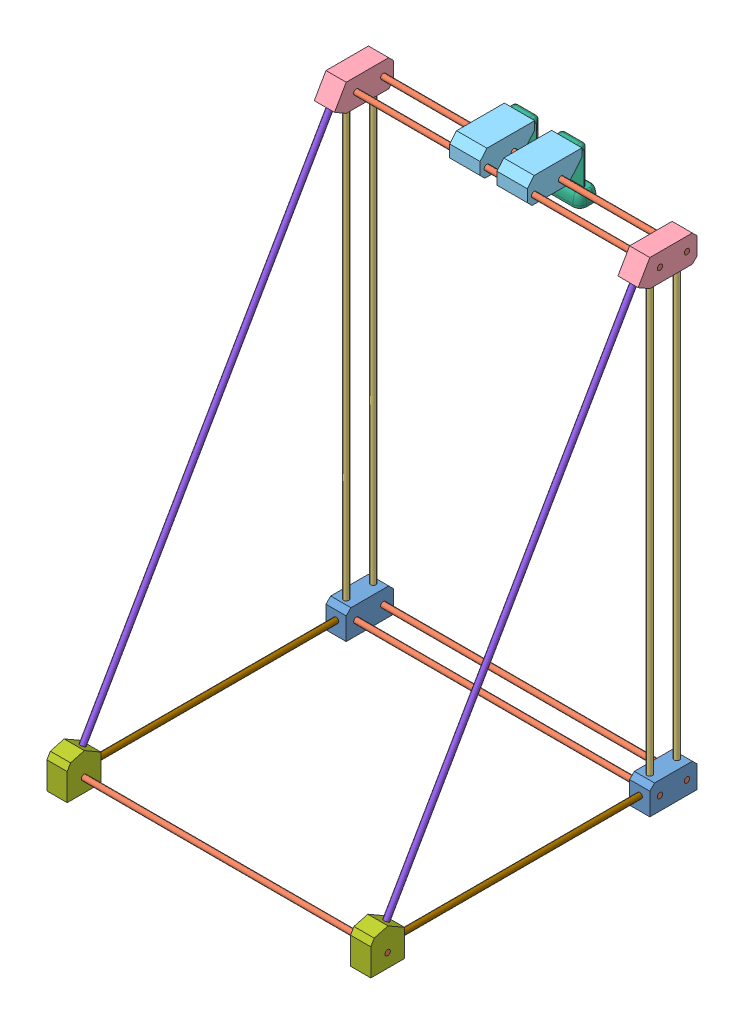
SolidWorks assembly M05, configuration Valor predeterminado. Lengths in mm.
Overall size (480 722.44 521.52).
27 component instances, 9 part files, 0 mates.
Components (placement in the parent):
- M04-1: M04 [Valor predeterminado] at (667.0132 -86.308 -633.8307) size (480 722.44 521.52)
  - M01-1: M01 [Valor predeterminado] at (-363.1678 -147.1166 448.121) size (480 40 70)
    - S02-1: S02 [Valor predeterminado] at (67.124 0.9923 31.879) size (30 40 70)
    - S02-2: S02 [Valor predeterminado] at (517.124 0.9923 31.879) size (30 40 70)
    - B01-1: B01 [Valor predeterminado] at (292.124 0.9923 51.879) x (0 -0.668888 0.743363) z (-1 0 0) size (7.94 7.94 480)
    - B01-2: B01 [Valor predeterminado] at (292.124 0.9923 11.879) x (0 0 1) z (-1 0 0) size (7.94 7.94 480)
  - B02-1: B02 [Valor predeterminado] at (153.9562 192.8457 460) x (0.715397 0 0.698718) z (-0.698718 0 0.715397) size (7.94 670 7.94)
  - B02-2: B02 [Valor predeterminado] at (153.9562 192.8457 500) x (0.738581 0 0.674164) z (-0.674164 0 0.738581) size (7.94 670 7.94)
  - B02-3: B02 [Valor predeterminado] at (-296.0438 192.8457 460) x (-0.715397 0 0.698718) z (-0.698718 0 -0.715397) size (7.94 670 7.94)
  - B02-4: B02 [Valor predeterminado] at (-296.0438 192.8457 500) x (-0.738581 0 0.674164) z (-0.674164 0 -0.738581) size (7.94 670 7.94)
  - M03-1: M03 [Valor predeterminado] at (140.416 512.3832 399.7341) size (480 74.25 125.32)
    - S03-1: S03 [Valor predeterminado] at (13.5401 19.4326 80.2659) size (30 40 87.32)
    - B01-1: B01 [Valor predeterminado] at (-211.4599 19.4326 60.2659) x (0 -0.924225 -0.381849) z (1 0 0) size (7.94 7.94 480)
    - B01-2: B01 [Valor predeterminado] at (-211.4599 19.4326 100.2659) x (0 -0.924225 -0.381849) z (1 0 0) size (7.94 7.94 480)
    - S03-2: S03 [Valor predeterminado] at (-436.4599 19.4326 80.2659) size (30 40 87.32)
    - S05-1: S05 [Valor predeterminado] at (-250.5177 19.4326 80.2659) x (0 0 -1) z (1 0 0) size (80.98 37 45)
    - S05-2: S05 [Valor predeterminado] at (-180.5177 19.4326 80.2659) x (0 0 -1) z (1 0 0) size (80.98 37 45)
    - C01-1: C01 [Valor predeterminado] at (-188.2677 -12.3174 22.2884) x (-1 0 0) z (0 -1 0) size (70.05 47.02 73)
    - C01-2: C01 [Valor predeterminado] at (-258.2677 -12.3174 22.2884) x (-1 0 0) z (0 -1 0) size (70.05 47.02 73)
  - M02-2: M02 [Valor predeterminado] at (166.704 -133.6216 841.8715) size (480 54.15 50)
    - S01-1: S01 [Valor predeterminado] at (-12.7479 -12.5027 61.6506) size (30 54.15 50)
    - B01-1: B01 [Valor predeterminado] at (-237.7479 -12.5027 61.6506) x (0 -0.924225 -0.381849) z (1 0 0) size (7.94 7.94 480)
    - S01-2: S01 [Valor predeterminado] at (-462.7479 -12.5027 61.6506) size (30 54.15 50)
  - B03-1: B03 [Valor predeterminado] at (153.9562 201.5825 705.6603) x (-0.391168 0.46016 0.79702) z (-0.920319 -0.195584 -0.338762) size (7.94 768 7.94)
  - B03-2: B03 [Valor predeterminado] at (-296.0438 201.5825 705.6603) x (0.842145 -0.269626 -0.467005) z (0.539251 0.421072 0.729319) size (7.94 768 7.94)
  - B04-1: B04 [Valor predeterminado] at (153.9562 -146.1243 701.47) x (0.991411 0.130784 0) z (0 0 1) size (7.94 7.94 395)
  - B04-2: B04 [Valor predeterminado] at (-296.0438 -146.1243 701.47) x (0.729081 -0.684428 0) z (0 0 1) size (7.94 7.94 395)
